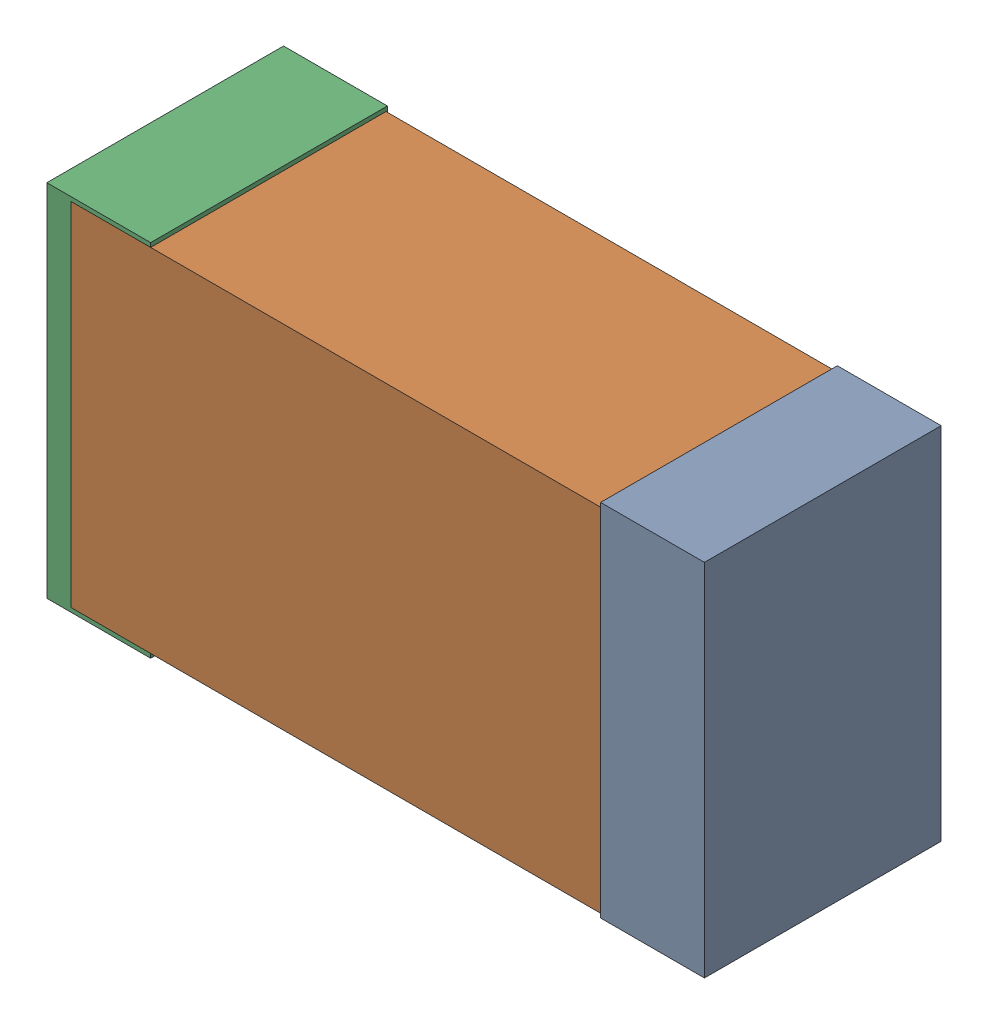
SolidWorks assembly USB01_FB3, configuration Default. Lengths in mm.
Overall size (2.38 1.3 0.85).
6 component instances, 2 part files, 0 mates.
Components (placement in the parent):
- 384311232-1: 384311232 [Default] at (163.814 72.009 -1.9574) size (0.38 1.3 0.85)
  - Extruded_8-1: Extruded_8 [Default] at origin size (0.38 1.3 0.85)
- 384311360-1: 384311360 [Default] at (162.814 72.009 -1.9524) size (2.2 1.27 0.85)
  - Extruded_9-1: Extruded_9 [Default] at origin size (2.2 1.27 0.85)
- 384311232-2: 384311232 [Default] at (161.814 72.009 -1.9574) size (0.38 1.3 0.85)
  - Extruded_8-1: Extruded_8 [Default] at origin size (0.38 1.3 0.85)
